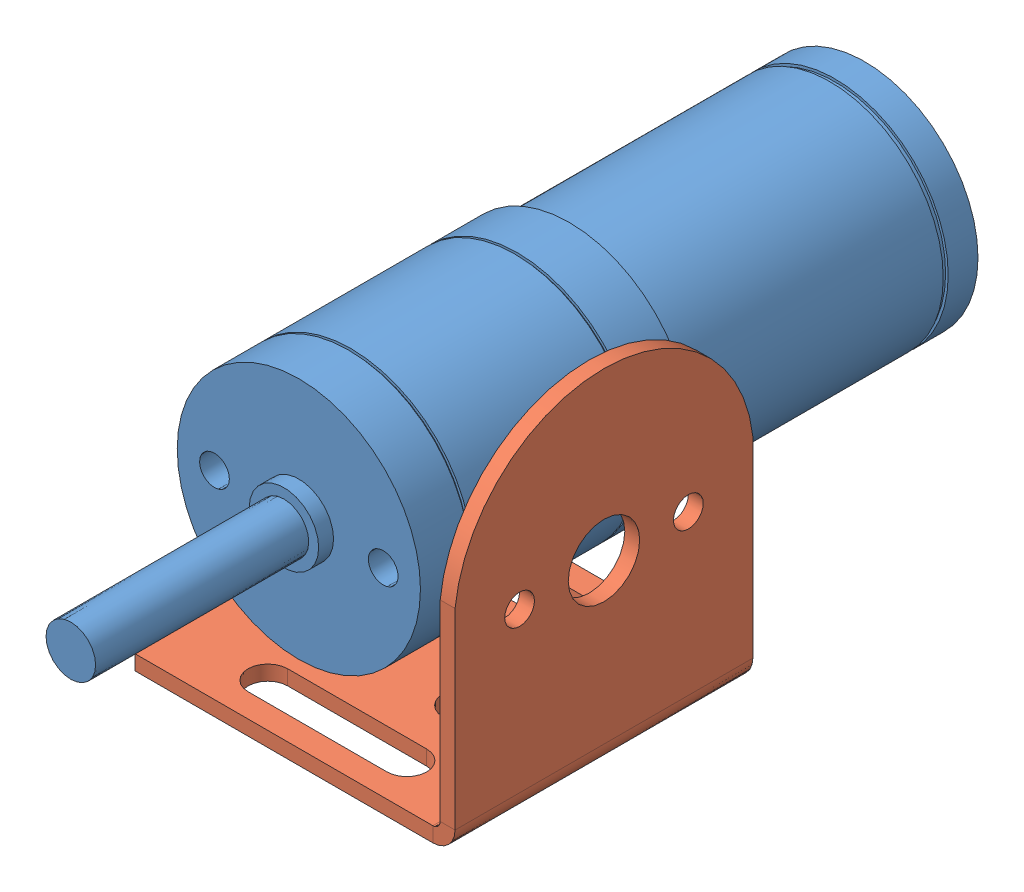
SolidWorks assembly DC motor 1.1, configuration Default. Lengths in mm.
Overall size (32.24 35 83.77).
2 component instances, 2 part files, 0 mates.
Components (placement in the parent):
- Dc motor 2-1: Dc motor 2 [Default] at (28.3871 37.9736 70.2822) size (24.5 24.5 83.77)
- DC motor Bracket-1: DC motor Bracket [Default] at (28.3871 19.4736 56.7822) x (0 0 -1) z (1 0 0) size (30 35 32.24)
